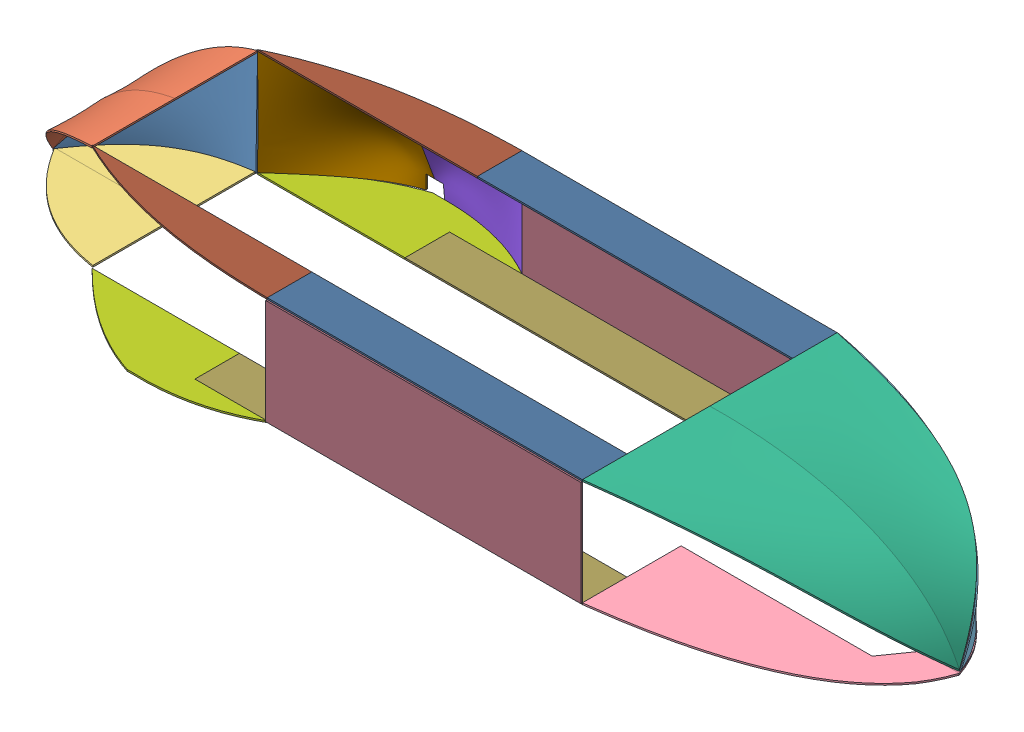
SolidWorks assembly ind body panels, configuration Default. Lengths in mm.
Overall size (3690.98 535.04 1245.02).
20 component instances, 13 part files, 16 mates.
Components (placement in the parent):
- Boss-Extrude11-1: Boss-Extrude11 [Default] at (1042.9954 -1349.0846 -704.2922) size (516.43 425.6 692.74)
- Boss-Extrude13-1: Boss-Extrude13 [Default] at (1045.052 -1351.2241 -709.5734) size (523.73 421.97 664.38)
- Boss-Extrude14-1: Boss-Extrude14 [Default] at (1040.8008 -1343.3633 -709.5734) size (482.6 6.35 330.2)
- Boss-Extrude15-1: Boss-Extrude15 [Default] at (1041.589 -1350.9937 -713.1064) size (995.11 6.35 508)
- Boss-Extrude16-1: Boss-Extrude16 [Default] at (1041.5889 -1350.9936 -713.1062) size (1064.61 535.04 1037.24)
- Boss-Extrude17-1: Boss-Extrude17 [Default] at (1041.5889 -1350.9936 -713.1062) size (1051.95 430.69 1027.1)
- Boss-Extrude18-1: Boss-Extrude18 [Default] at (1041.589 -1350.9937 -713.1064) size (876.3 6.35 283.09)
- Boss-Extrude20-1: Boss-Extrude20 [Default] at (1041.589 -1350.9937 -713.1064) size (462.61 454 1239.76)
- Boss-Extrude21-1: Boss-Extrude21 [Default] at (1041.589 -1350.9937 -713.1064) size (498.64 451.05 1245.02)
- Boss-Extrude5-1: Boss-Extrude5 [Default] at (1041.589 -1350.9937 -713.1064) size (1257.3 6.35 177.8)
- Boss-Extrude7-1: Boss-Extrude7 [Default] at (1041.589 -1350.9937 -713.1064) size (876.48 6.35 177.9)
- Boss-Extrude8-1: Boss-Extrude8 [Default] at (1041.589 -1350.9937 -713.1064) size (1545.9 6.35 177.8)
- Part27-1: Part27 [Default] at origin size (1257.3 419.1 6.35)
- Part27-2: Part27 [Default] at (0 0 1022.35) size (1257.3 419.1 6.35)
- Boss-Extrude8-2: Boss-Extrude8 [Default] at (1041.589 -1350.9937 125.0937) size (1545.9 6.35 177.8)
- Boss-Extrude7-2: Boss-Extrude7 [Default] at (1041.589 2298.3905 2189.8027) x (1 0 0) z (0 0 -1) size (876.48 6.35 177.9)
- Boss-Extrude5-2: Boss-Extrude5 [Default] at (1041.589 -1350.9937 125.0936) size (1257.3 6.35 177.8)
- Boss-Extrude14-2: Boss-Extrude14 [Default] at (1040.8008 1455.121 2186.2698) x (1 0 0) z (0 0 -1) size (482.6 6.35 330.2)
- Boss-Extrude15-2: Boss-Extrude15 [Default] at (1041.589 1447.4905 2189.8028) x (1 0 0) z (0 0 -1) size (995.11 6.35 508)
- Boss-Extrude18-2: Boss-Extrude18 [Default] at (1041.589 1447.4905 2189.8028) x (1 0 0) z (0 0 -1) size (876.3 6.35 283.09)
Mates (geometry in assembly coordinates):
- Coincident1: coincident: plane of Boss-Extrude16-1 through (2251.3397 470.5235 230.3483) normal (-1 0 0); plane of ? through (2251.3398 470.5234 223.9982) normal (1 0 0)
- Coincident2: coincident: line of Boss-Extrude16-1 through (2251.3397 470.5235 230.3483) axis (0 0 -1); line of ? through (2251.3398 470.5234 223.9982) axis (0 0 1)
- Coincident6: coincident: point of Boss-Extrude16-1; point of ?
- Coincident8: coincident: point of Boss-Extrude16-1; point of Boss-Extrude17-1
- Coincident9: coincident: line of Boss-Extrude5-1 through (994.0398 476.8734 230.3482) axis (0 0 1); line of Boss-Extrude7-1 through (994.0398 476.8734 408.1482) axis (0 0 -1)
- Coincident10: coincident: line of Boss-Extrude5-1 through (994.0398 476.8734 230.3482) axis (0 -1 0); line of Boss-Extrude7-1 through (994.0398 476.8734 230.3482) axis (0 -1 0)
- Coincident11: coincident: line of Boss-Extrude5-1 through (2251.3398 470.5234 230.3482) axis (-1 0 0); line of ? through (994.0398 470.5234 230.3482) axis (1 0 0)
- Coincident12: coincident: line of Boss-Extrude17-1 through (2251.3398 470.5234 230.3482) axis (0 1 0); line of Boss-Extrude5-1 through (2251.3398 476.8734 230.3482) axis (0 -1 0)
- Coincident13: coincident: point of Boss-Extrude16-1; point of Boss-Extrude8-1
- Coincident14: coincident: point of Boss-Extrude20-1; point of ?
- Coincident15: coincident: point of Boss-Extrude20-1; point of Boss-Extrude21-1
- Coincident16: coincident: point of Boss-Extrude15-1; point of Boss-Extrude16-1
- Coincident17: coincident: point of Boss-Extrude11-1; point of Boss-Extrude7-1
- Coincident20: coincident: point of Boss-Extrude18-1; point of Boss-Extrude20-1
- Coincident22: coincident: point of Boss-Extrude11-1; point of Boss-Extrude13-1
- Coincident23: coincident: point of Boss-Extrude11-1; point of Boss-Extrude14-1
